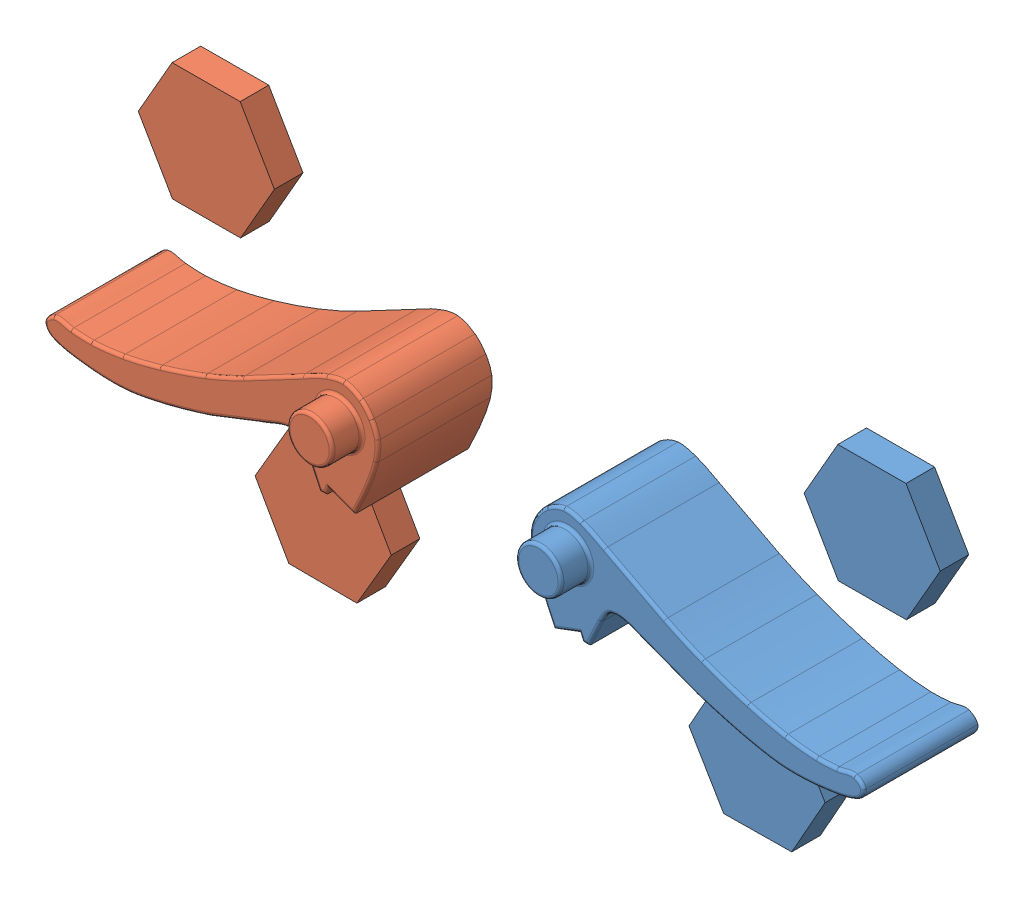
SolidWorks assembly New clip assembly, configuration Default. Lengths in mm.
Overall size (69.03 31.89 12.1).
2 component instances, 2 part files, 3 mates.
Components (placement in the parent):
- New clip 4-1: New clip 4 [Default] at (0.1082 -32.3565 114.6946) size (28.19 31.66 12.1)
- New clip 3-3: New clip 3 [Default] at (93.4319 -32.0444 114.6946) x (-0.999978 -0.006689 0) z (0 0 -1) size (28.14 31.66 12.1)
Mates (geometry in assembly coordinates):
- Coincident2: coincident: plane of New clip 4-1 through (0.1082 -32.3565 114.6946) normal (0 0 -1); plane of New clip 3-3 through (94.1794 -32.0419 114.6946) normal (0 0 -1)
- Coincident3: coincident: plane of New clip 4-1 through (77.1682 91.0469 112.2946) normal (-0.003344 0.999994 0); plane of New clip 3-3 through (16.2957 90.8433 117.0946) normal (-0.003344 0.999994 0)
- Distance1: distance = 25 mm: point of New clip 4-1; point of New clip 3-3
